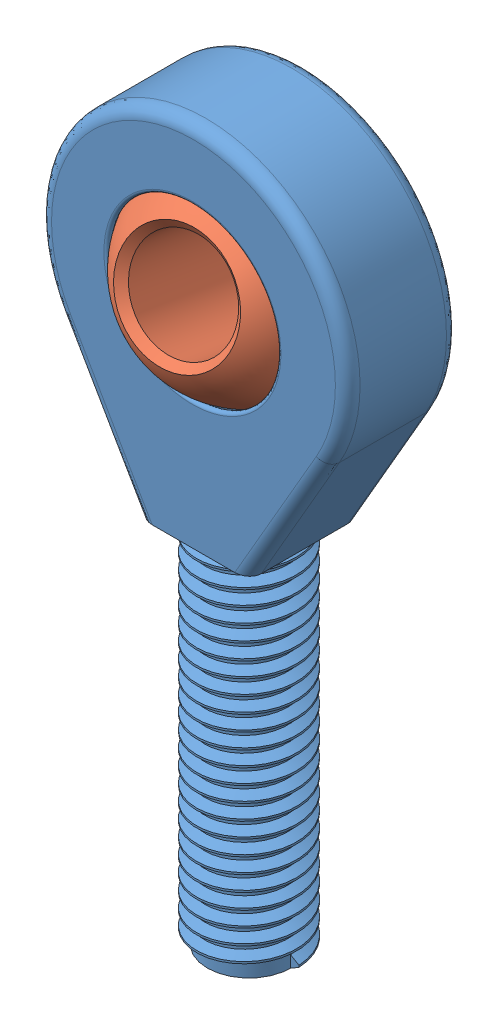
SolidWorks assembly Шарнир 8-8-30, configuration По умолчанию. Lengths in mm.
Overall size (25 59.71 18.46).
2 component instances, 2 part files, 1 mates.
Components (placement in the parent):
- Тело 16х8-1: Тело 16х8 [По умолчанию] at origin size (25 59.71 9.05)
- Шар 16х8-1: Шар 16х8 [По умолчанию] at (-0.1686 0 -0.0151) x (-0.943748 -0.285871 0.166187) z (0.097464 0.239767 0.965926) size (16 16 13.08)
Mates (geometry in assembly coordinates):
- Касательность1: tangent: torus of Тело 16х8-1; sphere of Шар 16х8-1
